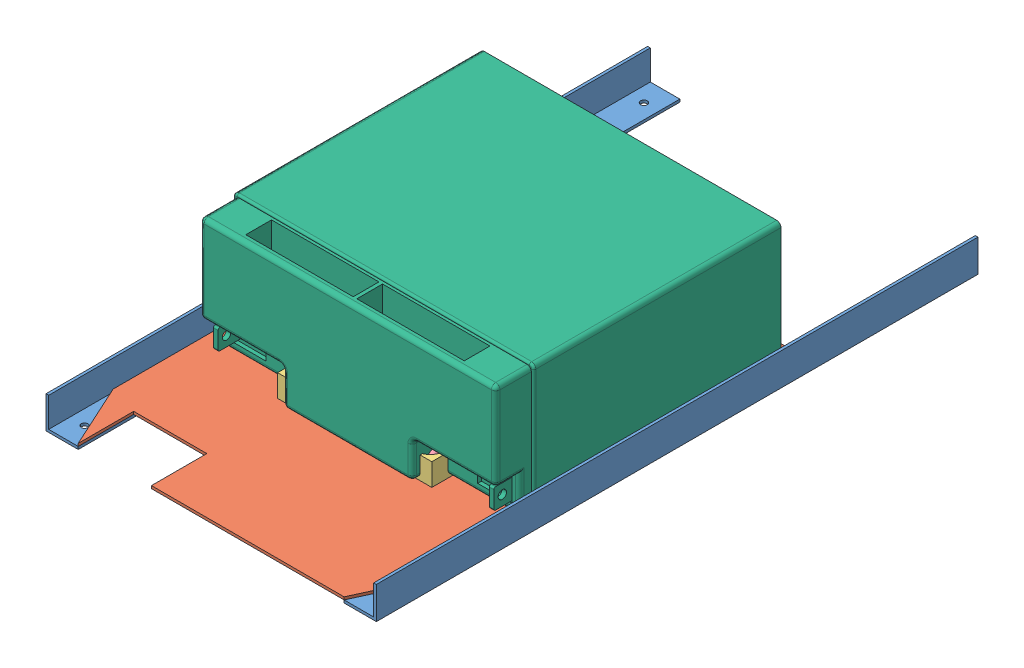
SolidWorks assembly batteryHolderAndCompressor, configuration Default. Lengths in mm.
Overall size (195.26 86.73 355.6).
9 component instances, 6 part files, 20 mates.
Components (placement in the parent):
- sideAngles-1: sideAngles [Default] at (28.0534 203.2819 133.3346) size (19.05 19.05 355.6)
- sideAngles-2: sideAngles [Default] at (223.3159 203.2819 488.9346) x (-1 0 0) z (0 0 -1) size (19.05 19.05 355.6)
- basePlate-1: basePlate [Default] at (125.6847 195.3444 311.1346) x (-1 0 0) z (0 0 -1) size (192.09 1.59 258.76)
- batteryholder-1: batteryholder [Default] at (83.0444 196.9319 389.646) x (-1 0 0) z (0 1 0) size (91.14 17.39 13.88)
- 92949A540_18-8 SS BUTTON-HEAD SOCKET CAP SCREW .25-20-1: 92949A540_18-8 SS BUTTON-HEAD SOCKET CAP SCREW .25-20 [92949A540] at (164.6165 209.2763 398.3392) x (0.997091 0 -0.076215) z (0 1 0) size (11.1 11.1 23.1)
- 92949A540_18-8 SS BUTTON-HEAD SOCKET CAP SCREW .25-20-2: 92949A540_18-8 SS BUTTON-HEAD SOCKET CAP SCREW .25-20 [92949A540] at (92.6075 209.2763 398.3392) x (0.987873 0 0.155266) z (0 1 0) size (11.1 11.1 23.1)
- 97135A210_GRADE 8 STEEL NYLON-INSERT LOCKNUT-1: 97135A210_GRADE 8 STEEL NYLON-INSERT LOCKNUT [97135A210] at (164.6165 195.3444 398.3392) x (0.70715 0 0.707063) z (0.707063 0 -0.70715) size (11.11 8.13 12.83)
- 97135A210_GRADE 8 STEEL NYLON-INSERT LOCKNUT-2: 97135A210_GRADE 8 STEEL NYLON-INSERT LOCKNUT [97135A210] at (92.6075 195.3444 398.3392) x (0.50806 0 0.861322) z (0.861322 0 -0.50806) size (11.11 8.13 12.83)
- battery_-2: battery_ [Default] at (184.9196 210.9186 244.5188) x (-1 0 0) z (0 0 1) size (177.8 76.2 167.13)
Mates (geometry in assembly coordinates):
- Coincident1: coincident: plane of sideAngles-1 through (28.0534 203.2819 133.3346) normal (0 0 -1); plane of sideAngles-2 through (223.3159 203.2819 133.3346) normal (0 0 -1)
- Coincident3: coincident: plane of sideAngles-1 through (47.1034 193.7569 488.9346) normal (0 -1 0); plane of sideAngles-2 through (204.2659 193.7569 133.3346) normal (0 -1 0)
- Coincident7: coincident: plane of sideAngles-2 through (221.7284 195.3444 133.3346) normal (0 1 0); plane of basePlate-1 through (125.6847 195.3444 311.1346) normal (0 -1 0)
- Coincident13: coincident: plane of sideAngles-2 through (223.3159 203.2819 488.9346) normal (0 0 1); plane of basePlate-1 through (221.7284 196.9319 488.9346) normal (0 0 1)
- Coincident14: coincident: plane of sideAngles-2 through (221.7284 212.8069 133.3346) normal (-1 0 0); plane of basePlate-1 through (221.7284 196.9319 133.3346) normal (1 0 0)
- Coincident15: coincident: plane of sideAngles-1 through (29.6409 212.8069 488.9346) normal (1 0 0); plane of basePlate-1 through (29.6409 196.9319 133.3346) normal (-1 0 0)
- Coincident17: coincident: plane of basePlate-1 through (125.6847 196.9319 311.1346) normal (0 1 0); line of batteryholder-1 through (83.0444 196.9319 407.0323) axis (1 0 0)
- Distance4: distance = 47.5488 mm: plane of batteryholder-1 through (174.1796 210.1145 389.646) normal (1 0 0); line of basePlate-1 through (221.7284 196.9319 230.1721) axis (0 0 1)
- Distance5: distance = 81.9023 mm: plane of batteryholder-1 through (83.0444 210.1145 407.0323) normal (0 0 1); plane of basePlate-1 through (221.7284 196.9319 488.9346) normal (0 0 1)
- Concentric1: concentric: circle of batteryholder-1; circle of 92949A540_18-8 SS BUTTON-HEAD SOCKET CAP SCREW .25-20-2
- Coincident19: coincident: plane of batteryholder-1 through (85.4638 205.9235 398.3392) normal (0 1 0); plane of 92949A540_18-8 SS BUTTON-HEAD SOCKET CAP SCREW .25-20-2 through (91.7458 205.9235 403.8218) normal (0 -1 0)
- Coincident20: coincident: plane of batteryholder-1 through (157.4728 205.9235 398.3392) normal (0 1 0); circle of 92949A540_18-8 SS BUTTON-HEAD SOCKET CAP SCREW .25-20-1
- Concentric2: concentric: circle of batteryholder-1; circle of 92949A540_18-8 SS BUTTON-HEAD SOCKET CAP SCREW .25-20-1
- Concentric3: concentric: circle of 92949A540_18-8 SS BUTTON-HEAD SOCKET CAP SCREW .25-20-2; circle of 97135A210_GRADE 8 STEEL NYLON-INSERT LOCKNUT-2
- Coincident21: coincident: plane of basePlate-1 through (125.6847 195.3444 311.1346) normal (0 -1 0); plane of 97135A210_GRADE 8 STEEL NYLON-INSERT LOCKNUT-2 through (92.6674 195.3444 404.7547) normal (0 1 0)
- Coincident22: coincident: plane of basePlate-1 through (125.6847 195.3444 311.1346) normal (0 -1 0); plane of 97135A210_GRADE 8 STEEL NYLON-INSERT LOCKNUT-1 through (166.2774 195.3444 404.5363) normal (0 1 0)
- Concentric4: concentric: circle of 92949A540_18-8 SS BUTTON-HEAD SOCKET CAP SCREW .25-20-1; circle of 97135A210_GRADE 8 STEEL NYLON-INSERT LOCKNUT-1
- Coincident28: coincident: plane of basePlate-1 through (125.6847 196.9319 311.1346) normal (0 1 0); plane of battery_-2 through (184.9196 196.9319 244.5188) normal (0 -1 0)
- Coincident29: coincident: plane of batteryholder-1 through (83.0444 210.1145 407.0323) normal (0 0 1); plane of battery_-2 through (163.6767 217.4592 407.0323) normal (0 0 -1)
- Coincident31: coincident: plane of batteryholder-1 through (130.6567 210.813 407.0323) normal (-1 0 0); plane of battery_-2 through (130.6567 217.4592 407.0323) normal (1 0 0)
